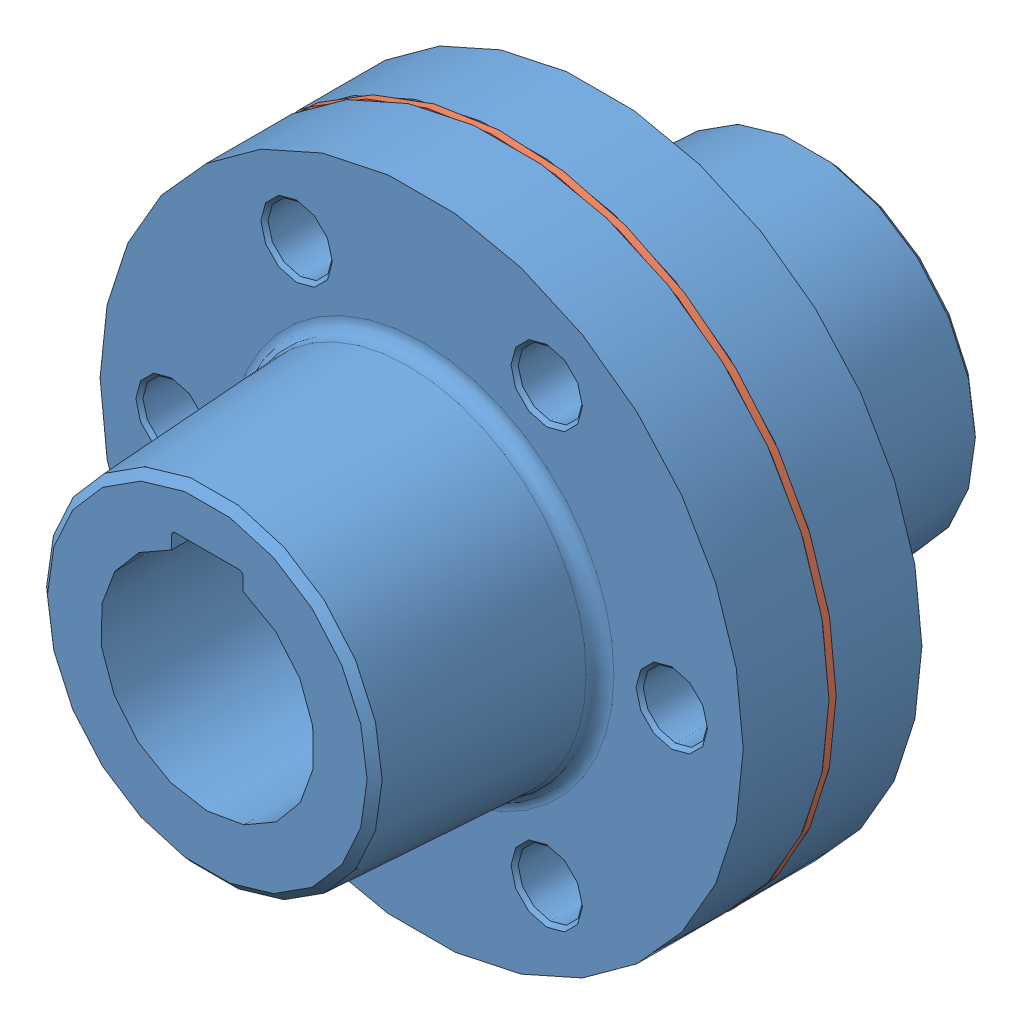
SolidWorks assembly Sestava1, configuration Default. Lengths in mm.
Overall size (90 90 85).
3 component instances, 2 part files, 7 mates.
Components (placement in the parent):
- Příruba-1: Příruba [Default] at origin size (90 90 42)
- Těsnění-1: Těsnění [Default] x (-1 0 0) z (0 0 -1) size (90 90 1)
- Příruba-2: Příruba [Default] at (0 0 -1) x (-1 0 0) z (0 0 -1) size (90 90 42)
Mates (geometry in assembly coordinates):
- Namístě1: in place: plane of Příruba-1 through (0 0 0) normal (0 0 -1); plane of Těsnění-1 through (0 0 0) normal (0 0 -1); moOrthogonalPlaneRef_w of Příruba-1 through (0 0 0) normal (0 0 -1); plane of Těsnění-1 through (0 0 0) normal (0 1 0); plane of Příruba-1 through (0 0 0) normal (0 0 -1); plane of Těsnění-1 through (0 0 0) normal (-1 0 0); plane of Příruba-1 through (0 0 0) normal (0 0 -1); unknown of Těsnění-1
- Sjednocená1: coincident aligned: plane of Příruba-1; plane of Těsnění-1
- Sjednocená2: coincident aligned: moOrthogonalPlaneRef_w of Příruba-1 through (0 0 0) normal (0 1 0); plane of Těsnění-1 through (0 0 0) normal (0 1 0)
- Sjednocená3: coincident anti-aligned: moOrthogonalPlaneRef_w of Příruba-1 through (0 0 0) normal (1 0 0); plane of Těsnění-1 through (0 0 0) normal (-1 0 0)
- Sjednocená4: coincident: plane of Těsnění-1 through (0 0 -1) normal (0 0 -1); plane of Příruba-2 through (-0.0991 0.0801 0) normal (0 0 1)
- Sjednocená5: coincident: cylinder of Těsnění-1 through (0 0 -1) axis (0 0 1) radius 45; circle of Příruba-2
- Soustředná2: concentric anti-aligned: cylinder of Příruba-1 through (17.5 30.3109 -0.001) axis (0 0 1) radius 4.5; cylinder of Příruba-2 through (17.5 30.3109 -0.999) axis (0 0 -1) radius 4.5
